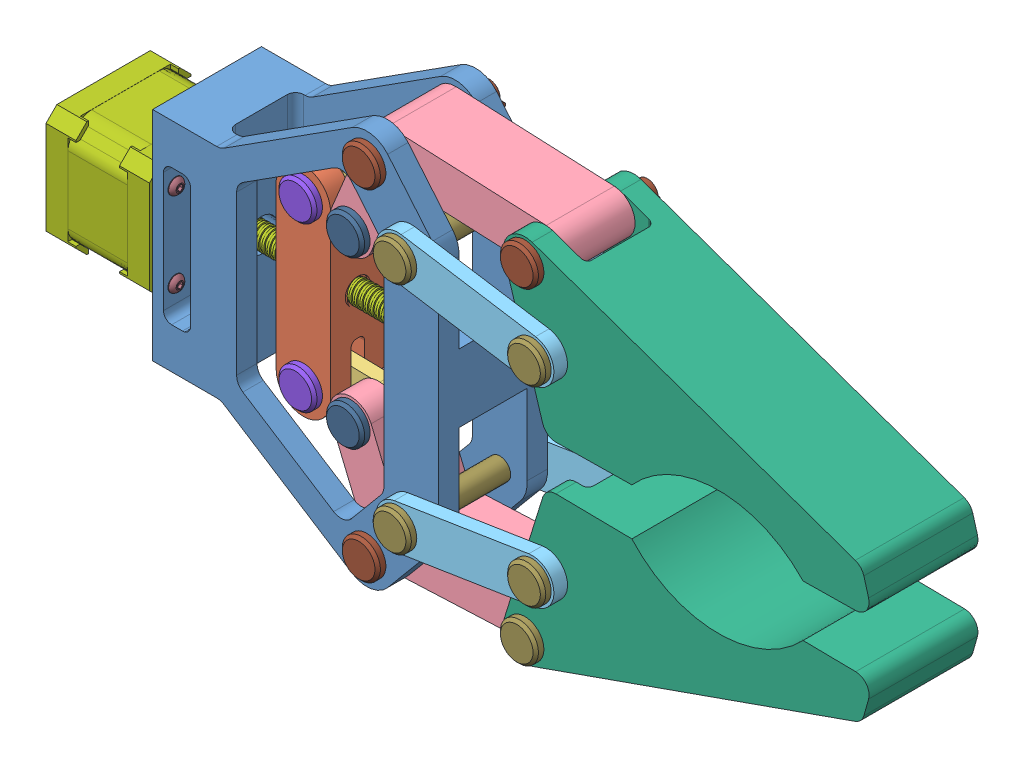
SolidWorks assembly Assembly, configuration Default. Lengths in mm.
Overall size (303.12 184.35 63).
30 component instances, 13 part files, 69 mates.
Components (placement in the parent):
- Part1-1: Part1 [Default] at origin size (105.05 145 40)
- Part2-1: Part2 [Default] at (45.4064 10 -10) size (23.33 80 20)
- Part3-1: Part3 [Default] at (45.4064 70 -17.5) x (0.999779 0.021039 0) z (0 0 1) size (35 15 5)
- Part3-2: Part3 [Default] at (45.4064 10 -17.5) x (0.999779 -0.021039 0) z (0 0 1) size (35 15 5)
- Part4-1: Part4 [Default] at (65.4019 70.4208 -7.5) x (0.916329 -0.400427 0) z (0 0 1) size (70.24 71.61 25)
- Part4-2: Part4 [Default] at (65.4019 9.5792 -32.5) x (0.916329 0.400427 0) z (0 0 -1) size (70.24 71.61 25)
- Part6-1: Part6 [Default] at (95.05 82.95 5) x (0.987777 -0.155872 0) z (0 0 1) size (66 16 5)
- Part6-2: Part6 [Default] at (95.05 82.95 -45) x (0.987777 -0.155872 0) z (0 0 -1) size (66 16 5)
- Part5-1: Part5 [Default] at (136.7666 99.9229 0) x (0.999905 0.013791 0) z (0 0 1) size (133.82 59.87 40)
- Part5-2: Part5 [Default] at (136.7666 -19.9229 -40) x (0.999905 -0.013791 0) z (0 0 -1) size (133.82 59.87 40)
- Part6-4: Part6 [Default] at (95.05 -2.95 -40) x (0.987777 0.155872 0) z (0 0 1) size (66 16 5)
- Part6-5: Part6 [Default] at (95.05 -2.95 5) x (0.987777 0.155872 0) z (0 0 1) size (66 16 5)
- Part11-1: Part11 [Valor predeterminado] at (-8 40 -20) x (0 -1 0) z (0 0 1) size (42.3 140.04 42.3)
- Part7-1: Part7 [Default] at (45.4064 70 -10) x (0 1 0) z (-1 0 0) size (14 28 14)
- Part12-1: Part12 [Default] at (95.95 40 -20) x (0 0 -1) z (1 0 0) size (13.6 13.6 3.5)
- Part7-2: Part7 [Default] at (45.4064 10 -10) x (0 1 0) z (-1 0 0) size (14 28 14)
- Part9-3: Part9 [Default] at (65.4019 9.5792 -7.5) x (0 1 0) z (-1 0 0) size (14 38 14)
- Part9-4: Part9 [Default] at (65.4019 70.4208 -7.5) x (0 1 0) z (-1 0 0) size (14 38 14)
- Part10-2: Part10 [Default] at (136.7666 99.9229 0) x (0 -1 0) z (1 0 0) size (14 48 14)
- Part8-3: Part8 [Default] at (136.7666 -19.9229 0) x (0 -1 0) z (1 0 0) size (14 58 14)
- Part8-4: Part8 [Default] at (144.4389 75.1564 5) x (0 1 0) z (-1 0 0) size (14 58 14)
- Part8-5: Part8 [Default] at (144.4389 4.8436 5) x (0 1 0) z (-1 0 0) size (14 58 14)
- Part8-6: Part8 [Default] at (95.05 -2.95 5) x (0 1 0) z (-1 0 0) size (14 58 14)
- Part8-7: Part8 [Default] at (95.05 82.95 5) x (0 1 0) z (-1 0 0) size (14 58 14)
- Part10-3: Part10 [Default] at (78.7 102.5 0) x (0 1 0) z (-1 0 0) size (14 48 14)
- Part10-4: Part10 [Default] at (78.7 -22.5 0) x (0 1 0) z (-1 0 0) size (14 48 14)
- Part13-1: Part13 [Default] at (5.65 24.5 -4.5) x (0 0.091887 -0.995769) z (1 0 0) size (5.74 5.77 8.05)
- Part13-2: Part13 [Default] at (5.65 55.5 -4.5) x (0 0.091887 -0.995769) z (1 0 0) size (5.74 5.77 8.05)
- Part13-4: Part13 [Default] at (5.65 24.5 -35.5) x (0 0.091887 -0.995769) z (1 0 0) size (5.74 5.77 8.05)
- Part13-5: Part13 [Default] at (5.65 55.5 -35.5) x (0 0.091887 -0.995769) z (1 0 0) size (5.74 5.77 8.05)
Mates (geometry in assembly coordinates):
- Concentric1: concentric aligned: cylinder of Part1-1 through (100 40 -20) axis (-1 0 0) radius 6; cylinder of Part2-1 through (55.4064 40 -20) axis (-1 0 0) radius 3.85
- Concentric2: concentric aligned: cylinder of Part2-1 through (45.4064 70 -30) axis (0 0 1) radius 4; cylinder of Part3-1 through (45.4064 70 -22.5) axis (0 0 1) radius 4
- Coincident1: coincident anti-aligned: plane of Part2-1 through (55.4064 85 -17.5) normal (0 0 -1); plane of Part3-1 through (45.4064 70 -17.5) normal (0 0 1)
- Concentric3: concentric aligned: cylinder of Part2-1 through (45.4064 10 -30) axis (0 0 1) radius 4; cylinder of Part3-2 through (45.4064 10 -22.5) axis (0 0 1) radius 4
- Coincident2: coincident anti-aligned: plane of Part2-1 through (55.4064 -5 -22.5) normal (0 0 1); plane of Part3-2 through (45.4064 10 -22.5) normal (0 0 -1)
- Concentric4: concentric aligned: cylinder of Part4-1 through (78.7 102.5 -32.5) axis (0 0 1) radius 4; cylinder of Part1-1 through (78.7 102.5 -40) axis (0 0 1) radius 4
- Width1: width anti-aligned: plane of Part4-1 through (65.4019 70.4208 -7.5) normal (0 0 1); plane of Part4-1 through (65.4019 70.4208 -32.5) normal (0 0 -1); plane of Part1-1 through (20 -32.5 -7.5) normal (0 0 -1); plane of Part1-1 through (20 -32.5 -32.5) normal (0 0 1)
- Concentric5: concentric aligned: cylinder of Part3-1 through (65.4019 70.4208 -22.5) axis (0 0 1) radius 4; cylinder of Part4-1 through (65.4019 70.4208 -32.5) axis (0 0 1) radius 4
- Width2: width anti-aligned: plane of Part4-2 through (65.4019 9.5792 -7.5) normal (0 0 1); plane of Part4-2 through (65.4019 9.5792 -32.5) normal (0 0 -1); plane of Part1-1 through (20 -32.5 -7.5) normal (0 0 -1); plane of Part1-1 through (20 -32.5 -32.5) normal (0 0 1)
- Concentric7: concentric anti-aligned: cylinder of Part3-2 through (65.4019 9.5792 -22.5) axis (0 0 1) radius 4; cylinder of Part4-2 through (65.4019 9.5792 -7.5) axis (0 0 -1) radius 4
- Concentric8: concentric aligned: cylinder of Part1-1 through (95.05 82.95 -40) axis (0 0 1) radius 4; cylinder of Part6-1 through (95.05 82.95 0) axis (0 0 1) radius 4
- Coincident3: coincident anti-aligned: plane of Part1-1 through (78.7 102.5 0) normal (0 0 1); plane of Part6-1 through (95.05 82.95 0) normal (0 0 -1)
- Concentric9: concentric anti-aligned: cylinder of Part1-1 through (95.05 82.95 -40) axis (0 0 1) radius 4; cylinder of Part6-2 through (95.05 82.95 -40) axis (0 0 -1) radius 4
- Coincident4: coincident anti-aligned: plane of Part1-1 through (78.7 102.5 -40) normal (0 0 -1); plane of Part6-2 through (95.05 82.95 -40) normal (0 0 1)
- Concentric10: concentric aligned: cylinder of Part4-1 through (136.7666 99.9229 -32.5) axis (0 0 1) radius 4; cylinder of Part5-1 through (136.7666 99.9229 -40) axis (0 0 1) radius 4
- Concentric11: concentric aligned: cylinder of Part6-1 through (144.4389 75.1564 0) axis (0 0 1) radius 4; cylinder of Part5-1 through (144.4389 75.1564 -40) axis (0 0 1) radius 4
- Concentric12: concentric anti-aligned: cylinder of Part6-2 through (144.4389 75.1564 -40) axis (0 0 -1) radius 4; cylinder of Part5-1 through (144.4389 75.1564 -40) axis (0 0 1) radius 4
- Width3: width anti-aligned: plane of Part5-1 through (136.7666 99.9229 0) normal (0 0 1); plane of Part5-1 through (136.7666 99.9229 -40) normal (0 0 -1); plane of Part1-1 through (20 -32.5 -7.5) normal (0 0 -1); plane of Part1-1 through (20 -32.5 -32.5) normal (0 0 1)
- Concentric13: concentric aligned: cylinder of Part4-2 through (136.7666 -19.9229 -7.5) axis (0 0 -1) radius 4; cylinder of Part5-2 through (136.7666 -19.9229 0) axis (0 0 -1) radius 4
- Width4: width anti-aligned: plane of Part5-2 through (136.7666 -19.9229 0) normal (0 0 1); plane of Part5-2 through (136.7666 -19.9229 -40) normal (0 0 -1); plane of Part1-1 through (20 -32.5 -7.5) normal (0 0 -1); plane of Part1-1 through (20 -32.5 -32.5) normal (0 0 1)
- Concentric16: concentric aligned: cylinder of Part1-1 through (95.05 -2.95 -40) axis (0 0 1) radius 4; cylinder of Part6-4 through (95.05 -2.95 -45) axis (0 0 1) radius 4
- Concentric17: concentric anti-aligned: cylinder of Part5-2 through (144.4389 4.8436 0) axis (0 0 -1) radius 4; cylinder of Part6-4 through (144.4389 4.8436 -45) axis (0 0 1) radius 4
- Coincident6: coincident anti-aligned: plane of Part1-1 through (78.7 102.5 -40) normal (0 0 -1); plane of Part6-4 through (95.05 -2.95 -40) normal (0 0 1)
- Concentric19: concentric anti-aligned: cylinder of Part5-2 through (144.4389 4.8436 0) axis (0 0 -1) radius 4; cylinder of Part6-5 through (144.4389 4.8436 0) axis (0 0 1) radius 4
- Concentric20: concentric aligned: cylinder of Part1-1 through (95.05 -2.95 -40) axis (0 0 1) radius 4; cylinder of Part6-5 through (95.05 -2.95 0) axis (0 0 1) radius 4
- Coincident7: coincident anti-aligned: plane of Part1-1 through (78.7 102.5 0) normal (0 0 1); plane of Part6-5 through (95.05 -2.95 0) normal (0 0 -1)
- Concentric21: concentric anti-aligned: cylinder of Part1-1 through (78.7 -22.5 -40) axis (0 0 1) radius 4; cylinder of Part4-2 through (78.7 -22.5 -7.5) axis (0 0 -1) radius 4
- Coincident8: coincident anti-aligned: plane of Part1-1 through (0 0 -40) normal (-1 0 0); plane of Part11-1 through (0 40 -20) normal (1 0 0)
- Concentric22: concentric aligned: cylinder of Part1-1 through (100 40 -20) axis (-1 0 0) radius 6; cylinder of Part11-1 through (1.5 40 -20) axis (-1 0 0) radius 11
- Concentric23: concentric aligned: cylinder of Part2-1 through (45.4064 70 -30) axis (0 0 1) radius 4; cylinder of Part7-1 through (45.4064 70 -35) axis (0 0 1) radius 4
- Coincident9: coincident anti-aligned: plane of Part2-1 through (45.4064 70 -10) normal (0 0 1); plane of Part7-1 through (45.4064 70 -10) normal (0 0 -1)
- Parallel1: parallel anti-aligned: plane of Part1-1 through (30.8528 71.8732 -40) normal (1 0 0); plane of Part7-1 through (45.4064 70 -10) normal (-1 0 0)
- Concentric24: concentric anti-aligned: cylinder of Part1-1 through (100 40 -20) axis (-1 0 0) radius 6; cylinder of Part12-1 through (97.7 40 -20) axis (1 0 0) radius 4
- Coincident11: coincident anti-aligned: plane of Part1-1 through (95 0 0) normal (-1 0 0); plane of Part12-1 through (95 45.3736 -20) normal (1 0 0)
- Concentric25: concentric aligned: cylinder of Part2-1 through (45.4064 10 -30) axis (0 0 1) radius 4; cylinder of Part7-2 through (45.4064 10 -35) axis (0 0 1) radius 4
- Coincident12: coincident anti-aligned: plane of Part2-1 through (45.4064 70 -10) normal (0 0 1); plane of Part7-2 through (45.4064 10 -10) normal (0 0 -1)
- Parallel2: parallel anti-aligned: plane of Part1-1 through (30.8528 71.8732 -40) normal (1 0 0); plane of Part7-2 through (45.4064 10 -10) normal (-1 0 0)
- Coincident14: coincident anti-aligned: plane of Part4-2 through (65.4019 9.5792 -7.5) normal (0 0 1); plane of Part9-3 through (65.4019 9.5792 -7.5) normal (0 0 -1)
- Concentric26: concentric anti-aligned: cylinder of Part4-2 through (65.4019 9.5792 -7.5) axis (0 0 -1) radius 4; cylinder of Part9-3 through (65.4019 9.5792 -42.5) axis (0 0 1) radius 4
- Parallel3: parallel anti-aligned: plane of Part1-1 through (30.8528 71.8732 -40) normal (1 0 0); plane of Part9-3 through (65.4019 9.5792 -7.5) normal (-1 0 0)
- Coincident16: coincident anti-aligned: plane of Part4-1 through (65.4019 70.4208 -7.5) normal (0 0 1); plane of Part9-4 through (65.4019 70.4208 -7.5) normal (0 0 -1)
- Concentric27: concentric aligned: cylinder of Part4-1 through (65.4019 70.4208 -32.5) axis (0 0 1) radius 4; cylinder of Part9-4 through (65.4019 70.4208 -42.5) axis (0 0 1) radius 4
- Parallel4: parallel anti-aligned: plane of Part1-1 through (30.8528 71.8732 -40) normal (1 0 0); plane of Part9-4 through (65.4019 70.4208 -7.5) normal (-1 0 0)
- Coincident18: coincident aligned: plane of Part5-1 through (136.7666 99.9229 0) normal (0 0 1); circle of Part10-2
- Coincident19: coincident aligned: circle of Part5-1; cylinder of Part10-2 through (136.7666 99.9229 -45) axis (0 0 1) radius 4
- Parallel5: parallel aligned: plane of Part1-1 through (30.8528 71.8732 -40) normal (1 0 0); plane of Part10-2 through (136.7666 99.9229 0) normal (1 0 0)
- Coincident21: coincident anti-aligned: plane of Part5-2 through (136.7666 -19.9229 0) normal (0 0 1); plane of Part8-3 through (136.7666 -19.9229 0) normal (0 0 -1)
- Concentric28: concentric anti-aligned: cylinder of Part5-2 through (136.7666 -19.9229 0) axis (0 0 -1) radius 4; cylinder of Part8-3 through (136.7666 -19.9229 -55) axis (0 0 1) radius 4
- Parallel6: parallel aligned: plane of Part1-1 through (30.8528 71.8732 -40) normal (1 0 0); plane of Part8-3 through (136.7666 -19.9229 0) normal (1 0 0)
- Coincident23: coincident anti-aligned: plane of Part6-1 through (95.05 82.95 5) normal (0 0 1); plane of Part8-4 through (144.4389 75.1564 5) normal (0 0 -1)
- Concentric29: concentric aligned: cylinder of Part6-1 through (144.4389 75.1564 0) axis (0 0 1) radius 4; cylinder of Part8-4 through (144.4389 75.1564 -50) axis (0 0 1) radius 4
- Parallel7: parallel anti-aligned: plane of Part1-1 through (30.8528 71.8732 -40) normal (1 0 0); plane of Part8-4 through (144.4389 75.1564 5) normal (-1 0 0)
- Coincident25: coincident anti-aligned: plane of Part6-5 through (95.05 -2.95 5) normal (0 0 1); plane of Part8-5 through (144.4389 4.8436 5) normal (0 0 -1)
- Concentric30: concentric aligned: cylinder of Part6-5 through (144.4389 4.8436 0) axis (0 0 1) radius 4; cylinder of Part8-5 through (144.4389 4.8436 -50) axis (0 0 1) radius 4
- Parallel8: parallel anti-aligned: plane of Part1-1 through (30.8528 71.8732 -40) normal (1 0 0); plane of Part8-5 through (144.4389 4.8436 5) normal (-1 0 0)
- Coincident27: coincident anti-aligned: plane of Part6-5 through (95.05 -2.95 5) normal (0 0 1); plane of Part8-6 through (95.05 -2.95 5) normal (0 0 -1)
- Concentric31: concentric aligned: cylinder of Part6-5 through (95.05 -2.95 0) axis (0 0 1) radius 4; cylinder of Part8-6 through (95.05 -2.95 -50) axis (0 0 1) radius 4
- Parallel9: parallel anti-aligned: plane of Part1-1 through (30.8528 71.8732 -40) normal (1 0 0); plane of Part8-6 through (95.05 -2.95 5) normal (-1 0 0)
- Coincident29: coincident anti-aligned: plane of Part6-1 through (95.05 82.95 5) normal (0 0 1); plane of Part8-7 through (95.05 82.95 5) normal (0 0 -1)
- Concentric32: concentric aligned: cylinder of Part6-1 through (95.05 82.95 0) axis (0 0 1) radius 4; cylinder of Part8-7 through (95.05 82.95 -50) axis (0 0 1) radius 4
- Parallel10: parallel anti-aligned: plane of Part1-1 through (30.8528 71.8732 -40) normal (1 0 0); plane of Part8-7 through (95.05 82.95 5) normal (-1 0 0)
- Coincident31: coincident anti-aligned: plane of Part1-1 through (78.7 102.5 0) normal (0 0 1); plane of Part10-3 through (78.7 102.5 0) normal (0 0 -1)
- Concentric33: concentric aligned: cylinder of Part1-1 through (78.7 102.5 -40) axis (0 0 1) radius 4; cylinder of Part10-3 through (78.7 102.5 -45) axis (0 0 1) radius 4
- Parallel11: parallel anti-aligned: plane of Part1-1 through (30.8528 71.8732 -40) normal (1 0 0); plane of Part10-3 through (78.7 102.5 0) normal (-1 0 0)
- Coincident33: coincident anti-aligned: plane of Part1-1 through (78.7 102.5 0) normal (0 0 1); plane of Part10-4 through (78.7 -22.5 0) normal (0 0 -1)
- Concentric34: concentric aligned: cylinder of Part1-1 through (78.7 -22.5 -40) axis (0 0 1) radius 4; cylinder of Part10-4 through (78.7 -22.5 -45) axis (0 0 1) radius 4
- Parallel12: parallel anti-aligned: plane of Part1-1 through (30.8528 71.8732 -40) normal (1 0 0); plane of Part10-4 through (78.7 -22.5 0) normal (-1 0 0)
- Concentric35: concentric aligned: cylinder of Part1-1 through (10 24.5 -4.5) axis (-1 0 0) radius 1.75; cylinder of Part13-1 through (-2 24.5 -4.5) axis (-1 0 0) radius 1.5
- Coincident35: coincident anti-aligned: plane of Part1-1 through (4 65 -10) normal (1 0 0); plane of Part13-1 through (4 21.6621 -4.7619) normal (-1 0 0)
